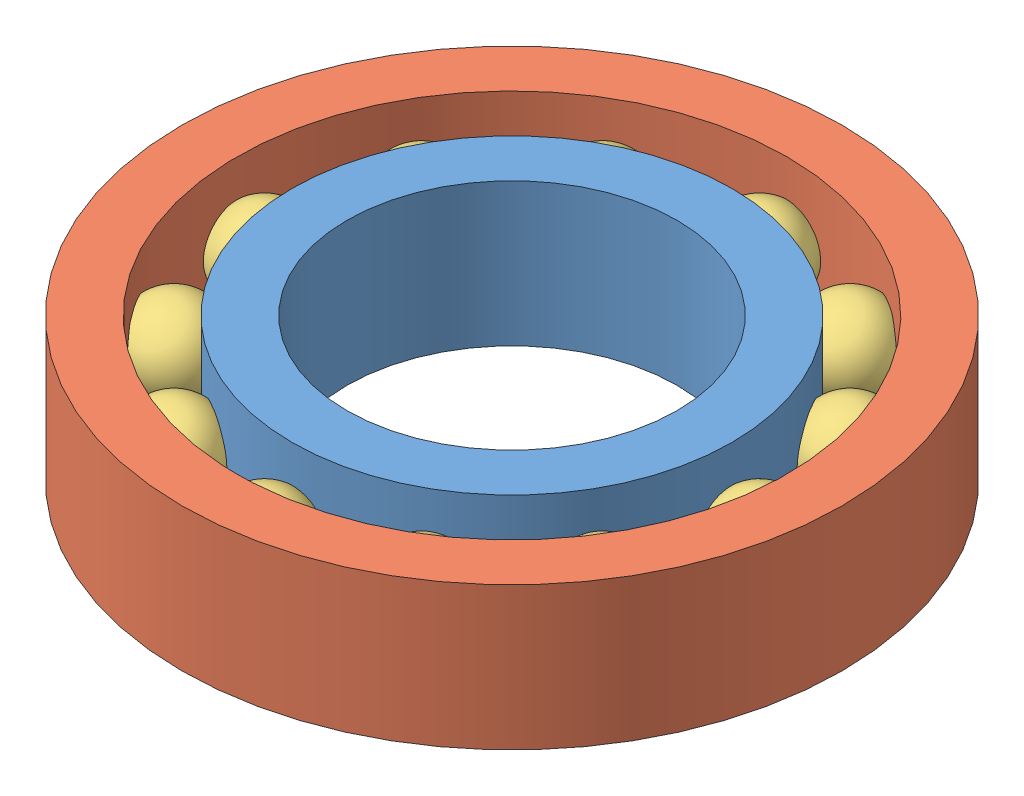
SolidWorks assembly BE101-01Z-03Z 滚珠轴承, configuration 默认. Lengths in mm.
Overall size (60 13 60).
14 component instances, 3 part files, 3 mates.
Components (placement in the parent):
- BE101-01Z-007 轴承内圈-1: BE101-01Z-007 轴承内圈 [默认] at origin size (40 13 40)
- BE101-01Z-006 轴承外圈-1: BE101-01Z-006 轴承外圈 [默认] at origin size (60 13 60)
- BE101-01Z-008 轴承滚珠-1: BE101-01Z-008 轴承滚珠 [默认] at (0 0 -22.5) size (8 8 8)
- BE101-01Z-008 轴承滚珠-2: BE101-01Z-008 轴承滚珠 [默认] at (11.25 0 -19.4856) x (0.866025 0 0.5) z (-0.5 0 0.866025) size (8 8 8)
- BE101-01Z-008 轴承滚珠-3: BE101-01Z-008 轴承滚珠 [默认] at (19.4856 0 -11.25) x (0.5 0 0.866025) z (-0.866025 0 0.5) size (8 8 8)
- BE101-01Z-008 轴承滚珠-4: BE101-01Z-008 轴承滚珠 [默认] at (22.5 0 0) x (0 0 1) z (-1 0 0) size (8 8 8)
- BE101-01Z-008 轴承滚珠-5: BE101-01Z-008 轴承滚珠 [默认] at (19.4856 0 11.25) x (-0.5 0 0.866025) z (-0.866025 0 -0.5) size (8 8 8)
- BE101-01Z-008 轴承滚珠-6: BE101-01Z-008 轴承滚珠 [默认] at (11.25 0 19.4856) x (-0.866025 0 0.5) z (-0.5 0 -0.866025) size (8 8 8)
- BE101-01Z-008 轴承滚珠-7: BE101-01Z-008 轴承滚珠 [默认] at (0 0 22.5) x (-1 0 0) z (0 0 -1) size (8 8 8)
- BE101-01Z-008 轴承滚珠-8: BE101-01Z-008 轴承滚珠 [默认] at (-11.25 0 19.4856) x (-0.866025 0 -0.5) z (0.5 0 -0.866025) size (8 8 8)
- BE101-01Z-008 轴承滚珠-9: BE101-01Z-008 轴承滚珠 [默认] at (-19.4856 0 11.25) x (-0.5 0 -0.866025) z (0.866025 0 -0.5) size (8 8 8)
- BE101-01Z-008 轴承滚珠-10: BE101-01Z-008 轴承滚珠 [默认] at (-22.5 0 0) x (0 0 -1) z (1 0 0) size (8 8 8)
- BE101-01Z-008 轴承滚珠-11: BE101-01Z-008 轴承滚珠 [默认] at (-19.4856 0 -11.25) x (0.5 0 -0.866025) z (0.866025 0 0.5) size (8 8 8)
- BE101-01Z-008 轴承滚珠-12: BE101-01Z-008 轴承滚珠 [默认] at (-11.25 0 -19.4856) x (0.866025 0 -0.5) z (0.5 0 0.866025) size (8 8 8)
Mates (geometry in assembly coordinates):
- Coincident1: coincident aligned: plane of BE101-01Z-008 轴承滚珠-1 through (0 0 -22.5) normal (1 0 0)
- Coincident2: coincident aligned: plane of BE101-01Z-008 轴承滚珠-1 through (0 0 -22.5) normal (0 1 0)
- Distance1: distance = 22.5 mm aligned: plane of BE101-01Z-008 轴承滚珠-1 through (0 0 -22.5) normal (0 0 1)
